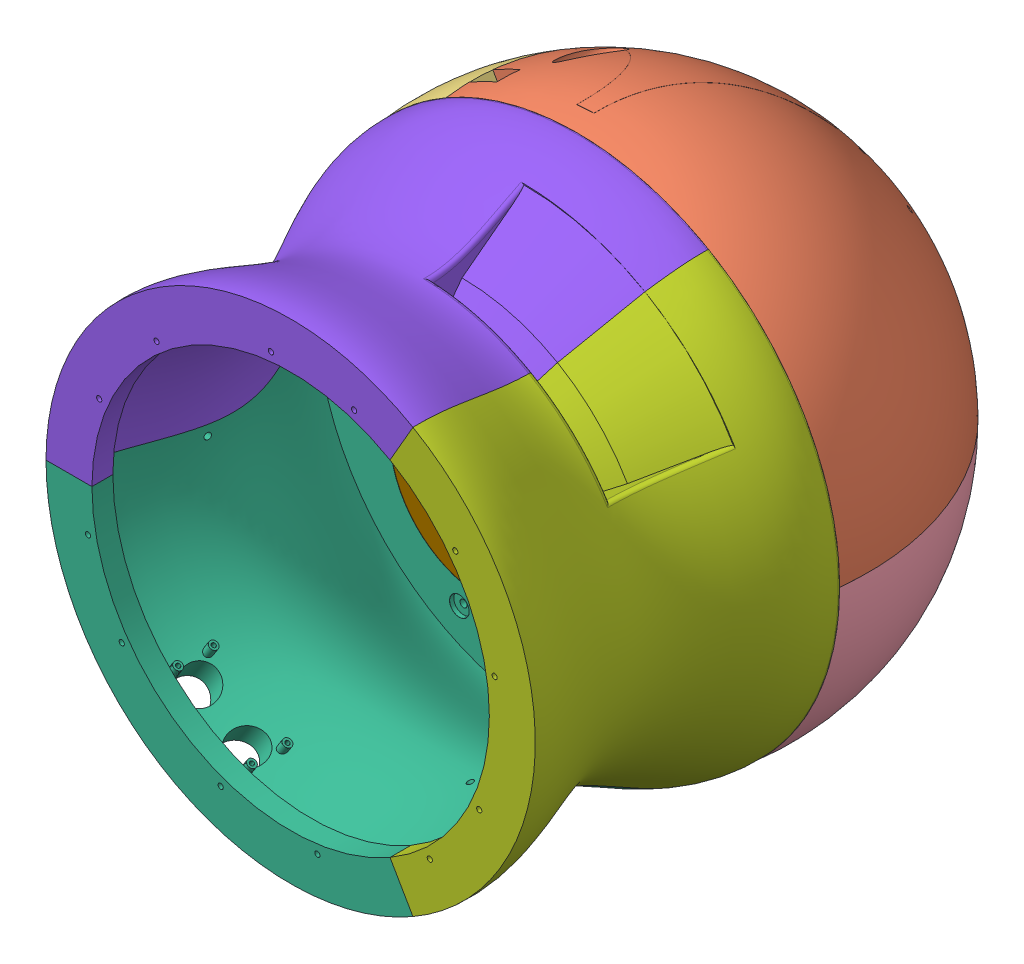
SolidWorks assembly finalAssembly2, configuration Défaut. Lengths in mm.
Overall size (315.86 335.79 321.06).
11 component instances, 11 part files, 28 mates.
Components (placement in the parent):
- hood_bottom-1: hood_bottom [Défaut] at (-59.4566 -23.9741 117.3244) x (0.000014 1 0) z (-1 0.000014 0) size (99.91 75.51 99.91)
- body_bottom_back-2: body_bottom_back [Défaut] at (-54.3842 -14.5209 215.9312) x (0.840134 -0.542378 0) z (-0.542378 -0.840134 0) size (218.81 181.14 229.88)
- body_bottom_left-1: body_bottom_left [Défaut] at (-70.1675 -24.3069 215.9312) x (0.049646 0.998767 0) z (0.998767 -0.049646 0) size (218.17 119.6 229.88)
- body_bottom_right-1: body_bottom_right [Défaut] at (-53.813 -33.0816 215.9312) x (-0.889781 -0.456389 0) z (-0.456389 0.889781 0) size (218.17 119.6 229.88)
- hood_top-1: hood_top [Défaut] at (-59.4572 -23.9731 228.2994) x (0.889337 0.457253 0) z (-0.457253 0.889337 0) size (168.25 11.5 168.25)
- body_middle_front-1: body_middle_front [Défaut] at (-63.3163 -31.3251 234.2138) x (-0.840146 0.54236 0) z (0.54236 0.840146 0) size (219.58 137 233.1)
- body_middle_handle_left-1: body_middle_handle_left [Défaut] at (-51.1607 -23.6392 234.2138) x (-0.049625 -0.998768 0) z (-0.998768 0.049625 0) size (219.58 137 233.1)
- body_middle_handle_right-1: body_middle_handle_right [Défaut] at (-63.3166 -16.6213 234.2138) x (-0.840123 -0.542397 0) z (-0.542397 0.840123 0) size (219.58 137 101.96)
- actuator_holder-1: actuator_holder [Défaut] at (-59.4572 -23.9731 279.0494) x (-0.889337 -0.457253 0) z (0 0 -1) size (120 120 45)
- sprocket_2-1: sprocket_2 [Défaut] at (-59.4572 -23.9731 279.0494) x (-0.889337 -0.457253 0) z (0 0 1) size (22 22 10)
- sprocket_1-1: sprocket_1 [Défaut] at (-59.4572 -23.9731 294.0494) x (0.889337 0.457253 0) z (0 0 -1) size (22 22 10)
Mates (geometry in assembly coordinates):
- Coaxiale7: concentric aligned: circle of hood_bottom-1; circle of body_bottom_back-2
- Coïncidente6: coincident anti-aligned: plane of hood_bottom-1 through (-59.4566 -23.9741 117.3244) normal (0 0 1); plane of body_bottom_back-2 through (-59.4503 -23.9631 117.3244) normal (0 0 -1)
- Coaxiale9: concentric aligned: circle of hood_bottom-1; circle of body_bottom_left-1
- Parallèle1: parallel anti-aligned: plane of body_bottom_back-2 through (-122.5081 85.2563 -14.9256) normal (-0.866025 -0.5 0); plane of body_bottom_left-1 through (-59.4572 -23.9731 -14.9256) normal (0.866025 0.5 0)
- Coïncidente9: coincident anti-aligned: plane of hood_bottom-1 through (-59.4566 -23.9741 117.3244) normal (0 0 1); plane of body_bottom_left-1 through (-59.4572 -23.9731 117.3244) normal (0 0 -1)
- Coïncidente10: coincident anti-aligned: plane of body_bottom_left-1 through (-122.5151 -133.1926 -14.9256) normal (0.866025 -0.5 0); plane of body_bottom_right-1 through (-59.4572 -23.9731 -14.9256) normal (-0.866025 0.5 0)
- Coïncidente11: coincident anti-aligned: plane of hood_bottom-1 through (-59.4566 -23.9741 117.3244) normal (0 0 1); plane of body_bottom_right-1 through (-59.4572 -23.9731 117.3244) normal (0 0 -1)
- Coïncidente13: coincident aligned: line of body_bottom_left-1 through (-86.0229 -69.9863 222.4052) axis (0 0 1); line of body_bottom_right-1 through (-86.0229 -69.9863 222.4052) axis (0 0 1)
- Coaxiale12: concentric anti-aligned: circle of hood_top-1; circle of body_bottom_left-1
- Coïncidente15: coincident anti-aligned: plane of body_bottom_left-1 through (-59.4572 -23.9731 228.2994) normal (0 0 1); plane of hood_top-1 through (-59.4572 -23.9731 228.2994) normal (0 0 -1)
- Coaxiale13: concentric aligned: circle of body_bottom_left-1; circle of hood_top-1
- Coaxiale14: concentric aligned: circle of body_bottom_left-1; circle of body_middle_front-1
- Coaxiale15: concentric aligned: circle of body_bottom_right-1; circle of body_middle_front-1
- Coïncidente16: coincident anti-aligned: plane of body_bottom_left-1 through (-180.1016 105.6155 233.9052) normal (0 0 1); plane of body_middle_front-1 through (-28.3253 -209.6964 233.9052) normal (0 0 -1)
- Coïncidente17: coincident anti-aligned: plane of body_bottom_right-1 through (-111.3621 -193.2486 233.9052) normal (0 0 1); plane of body_middle_handle_left-1 through (85.5566 95.8625 233.9052) normal (0 0 -1)
- Coïncidente18: coincident anti-aligned: plane of body_middle_front-1 through (3.603 -133.1912 -14.9256) normal (0.866015 0.500019 0); plane of body_middle_handle_left-1 through (-59.4572 -23.9731 -14.9256) normal (-0.866015 -0.500019 0)
- Coaxiale16: concentric anti-aligned: circle of body_bottom_right-1; circle of body_middle_handle_left-1
- Coïncidente19: coincident anti-aligned: plane of body_bottom_back-2 through (113.099 15.7237 233.9052) normal (0 0 1); plane of body_middle_handle_right-1 through (-28.1914 161.5317 233.9052) normal (0 0 -1)
- Coïncidente20: coincident anti-aligned: plane of body_middle_front-1 through (-59.4572 -23.9731 -14.9256) normal (-0.000022 1 0); plane of body_middle_handle_right-1 through (-59.4572 -23.9731 -14.9256) normal (0.000022 -1 0)
- Coïncidente21: coincident anti-aligned: plane of body_middle_handle_left-1 through (3.5983 85.2477 -14.9256) normal (-0.866036 0.499981 0); plane of body_middle_handle_right-1 through (3.5983 85.2477 -14.9256) normal (0.866036 -0.499981 0)
- Coaxiale17: concentric aligned: circle of hood_top-1; circle of actuator_holder-1
- Coaxiale18: concentric aligned: circle of hood_top-1; circle of actuator_holder-1
- Coïncidente22: coincident anti-aligned: plane of hood_top-1 through (-59.4572 -23.9731 234.0494) normal (0 0 1); plane of actuator_holder-1 through (-59.4572 -23.9731 234.0494) normal (0 0 -1)
- Coaxiale19: concentric aligned: circle of actuator_holder-1; circle of sprocket_2-1
- Coaxiale20: concentric aligned: circle of actuator_holder-1; circle of sprocket_2-1
- Coïncidente23: coincident anti-aligned: plane of actuator_holder-1 through (-59.4572 -23.9731 279.0494) normal (0 0 1); plane of sprocket_2-1 through (-59.4572 -23.9731 279.0494) normal (0 0 -1)
- Coïncidente28: coincident anti-aligned: plane of sprocket_2-1 through (-59.4572 -23.9731 289.0494) normal (0 0 1); plane of sprocket_1-1 through (-59.4572 -23.9731 289.0494) normal (0 0 -1)
- Coaxiale21: concentric anti-aligned: circle of sprocket_2-1; circle of sprocket_1-1
